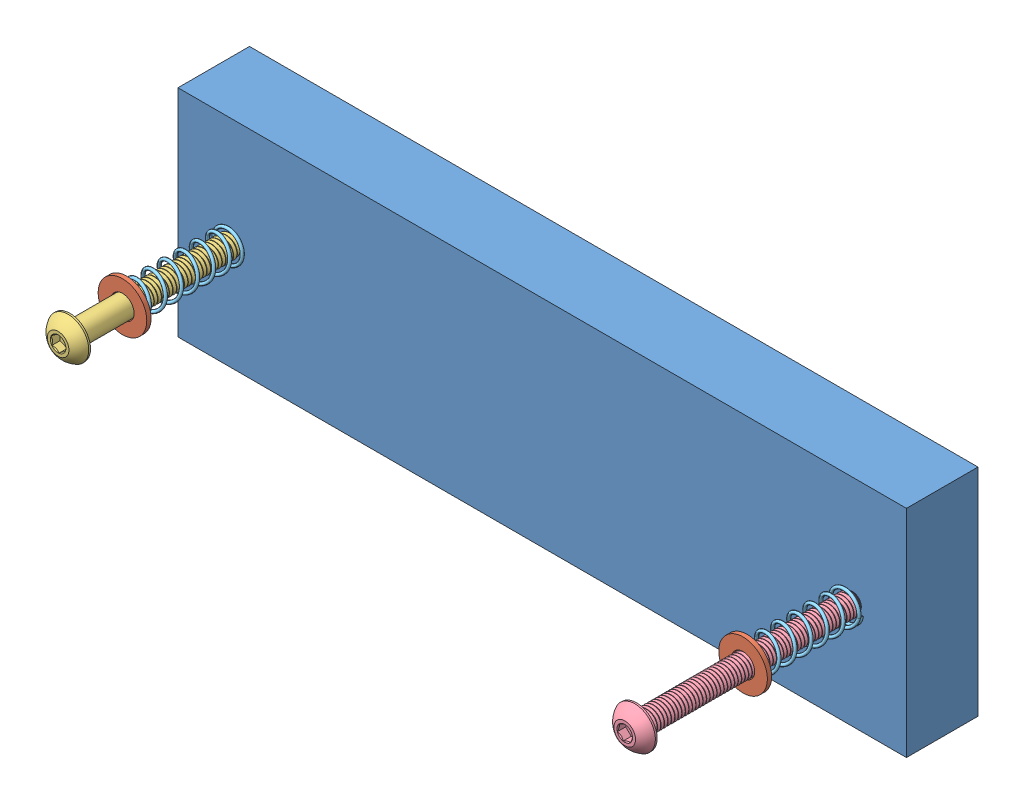
SolidWorks assembly BallWedgeAssembly, configuration Default. Lengths in mm.
Overall size (135 40 55.6).
7 component instances, 5 part files, 12 mates.
Components (placement in the parent):
- BallWedge-1: BallWedge [Default] at origin size (135 40 13.26)
- M4WasherFlat-1: M4WasherFlat [Default] at (-57.5 0 26.1078) x (0.94816 0.317793 0) z (0.317793 -0.94816 0) size (9 0.8 9)
- M4WasherFlat-2: M4WasherFlat [Default] at (57.5 0 26.9078) x (0.995865 0.09084 0) z (-0.09084 0.995865 0) size (9 0.8 9)
- M4x30pan-4: M4x30pan [92095A198] at (-57.5 0 38.83) x (-0.583863 0.811852 0) z (0 0 1) size (7.6 7.6 32.66)
- M4x40pan-4: M4x40pan [92095A200] at (57.5 0 48.83) x (0.675672 0.737202 0) z (0 0 1) size (7.6 7.6 42.77)
- Spring-1: Spring [9657K284] at (-57.5 0 26.1078) x (-0.068533 -0.997649 0) z (0 0 1) size (6.28 6.36 19.34)
- Spring-2: Spring [9657K284] at (57.5 0 26.6923) x (0.994166 -0.107862 0) z (0 0 1) size (6.28 6.36 19.34)
Mates (geometry in assembly coordinates):
- Coincident9: coincident aligned: plane of BallWedge-1 through (0 0 0) normal (0 0 1); plane of assembly through (0 0 0) normal (0 0 1)
- Coincident10: coincident aligned: plane of BallWedge-1 through (0 0 0) normal (0 1 0); plane of assembly through (0 0 0) normal (0 1 0)
- Coincident11: coincident aligned: plane of BallWedge-1 through (0 0 0) normal (1 0 0); plane of assembly through (0 0 0) normal (1 0 0)
- Coincident19: coincident anti-aligned: plane of M4x30pan-4 through (-55.8763 1.1677 6.63) normal (0 0 -1); plane of BallWedge-1 through (0 0 6.63) normal (0 0 1)
- Coincident20: coincident aligned: line of BallWedge-1 through (-57.5 0 -6.63) axis (0 0 1); line of M4x30pan-4 through (-57.5 0 6.63) axis (0 0 1)
- Coincident21: coincident aligned: line of M4x30pan-4 through (-57.5 0 6.63) axis (0 0 1); line of Spring-1 through (-57.5 0 6.0908) axis (0 0 1)
- Coincident22: coincident: point of M4WasherFlat-1; line of M4x30pan-4 through (-57.5 0 4.6872) axis (0 0 1)
- Concentric3: concentric aligned: cylinder of BallWedge-1 through (57.5 0 6.63) axis (0 0 1) radius 1.65; line of M4x40pan-4 through (57.5 0 4.0772) axis (0 0 1)
- Coincident23: coincident anti-aligned: plane of BallWedge-1 through (0 0 6.63) normal (0 0 1); plane of M4x40pan-4 through (58.9744 -1.3513 6.63) normal (0 0 -1)
- Coincident24: coincident aligned: line of M4x40pan-4 through (57.5 0 6.63) axis (0 0 1); line of Spring-2 through (57.5 0 6.6754) axis (0 0 1)
- Coincident26: coincident: point of M4WasherFlat-2; line of M4x40pan-4 through (57.5 0 6.63) axis (0 0 1)
- Coincident27: coincident aligned: plane of M4WasherFlat-1 through (-57.5 0 26.1078) normal (0 0 -1); plane of M4WasherFlat-2 through (57.5 0 26.1078) normal (0 0 -1)
